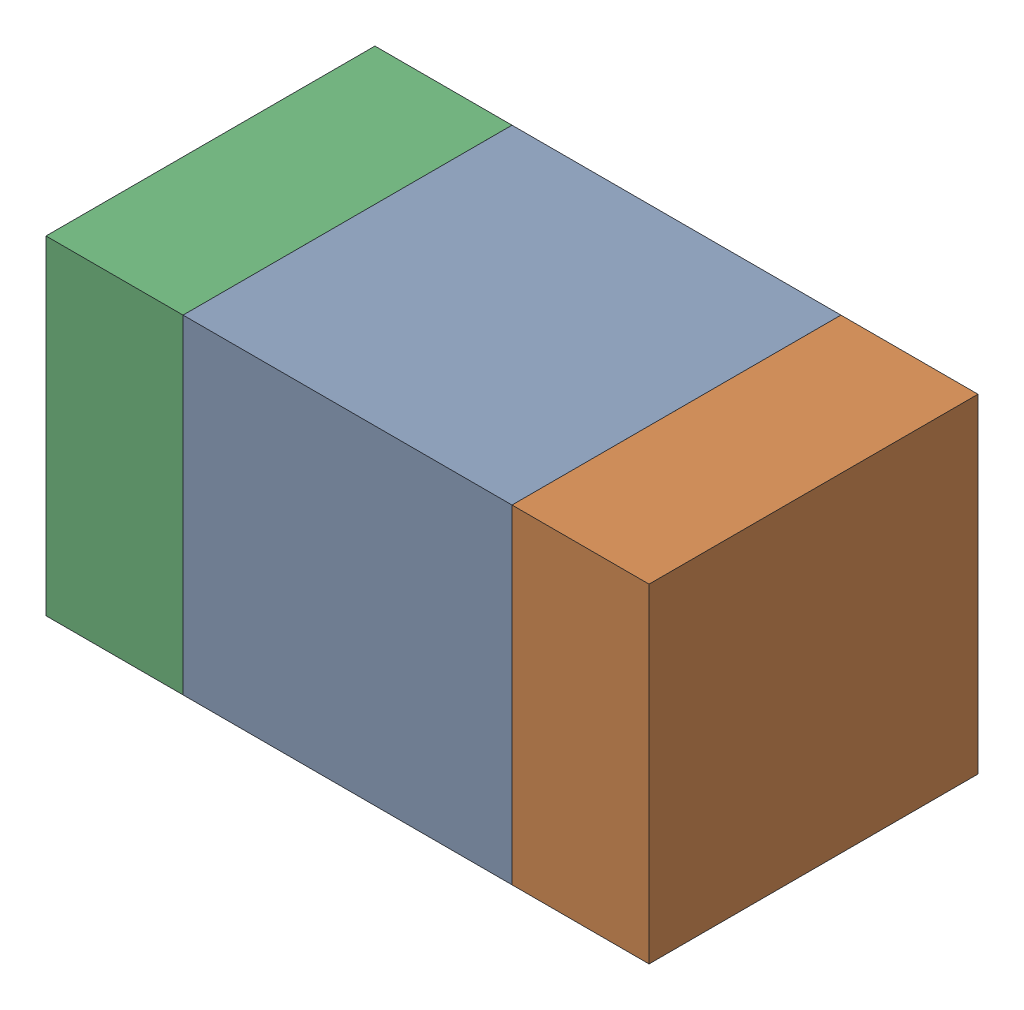
SolidWorks assembly C301_2PCB, configuration Default. Lengths in mm.
Overall size (1.1 0.6 0.6).
6 component instances, 2 part files, 0 mates.
Components (placement in the parent):
- 761606048-1: 761606048 [Default] at (145.6752 102.0181 0) size (0.6 0.6 0.6)
  - Extruded_9-1: Extruded_9 [Default] at origin size (0.6 0.6 0.6)
- 854785160-1: 854785160 [Default] at (146.1003 102.0181 0) size (0.25 0.6 0.6)
  - Extruded_19-1: Extruded_19 [Default] at origin size (0.25 0.6 0.6)
- 854785160-2: 854785160 [Default] at (145.2502 102.0181 0) size (0.25 0.6 0.6)
  - Extruded_19-1: Extruded_19 [Default] at origin size (0.25 0.6 0.6)
